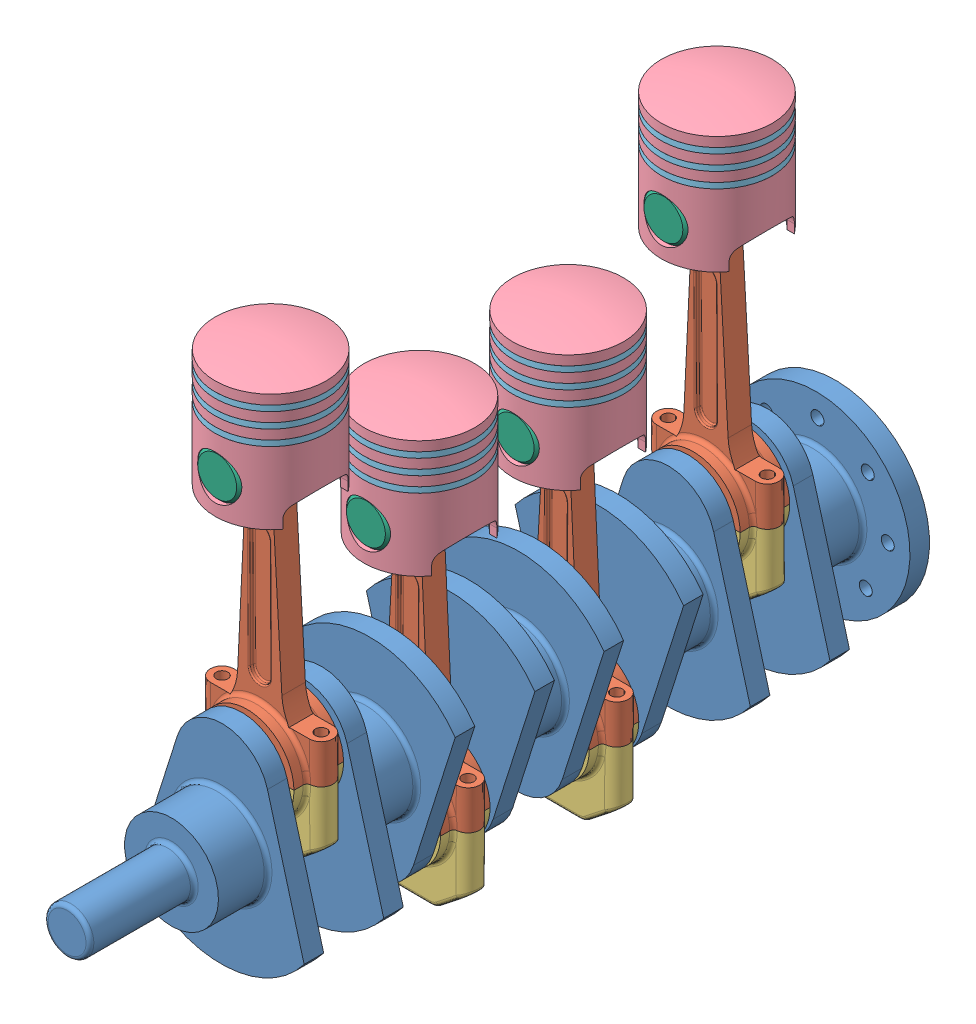
SolidWorks assembly Engine, configuration Default. Lengths in mm.
Overall size (147.06 418.41 589).
29 component instances, 6 part files, 66 mates.
Components (placement in the parent):
- Crankshaft-1: Crankshaft [Default] at (0 0 456) x (-0.999814 0.019293 0) z (0 0 1) size (144 160 589)
- Connecting rod-1: Connecting rod [Default] at (0 245.19 433) x (0.999991 0.004219 0) z (0 0 1) size (94 223.7 38)
- Connecting rod cap-1: Connecting rod cap [Default] at (0.8489 43.9918 433) x (-0.999991 -0.004219 0) z (0 0 1) size (94 60 38)
- Piston-1: Piston [Default] at (0 219.2199 433) size (85 95 85)
- Piston ring-1: Piston ring [Default] at (0 297.6199 433) size (85 4.3 85)
- Piston Pin-1: Piston Pin [Default] at (0 245.19 433) size (33.8 33.8 82)
- Piston ring-2: Piston ring [Default] at (0 286.0199 433) x (0.546944 0 -0.837169) z (0.837169 0 0.546944) size (85 4.3 85)
- Piston ring-4: Piston ring [Default] at (0 274.4199 433) x (0.546944 0 -0.837169) z (0.837169 0 0.546944) size (85 4.3 85)
- Piston-2: Piston [Default] at (0 131.2362 319) size (85 95 85)
- Piston ring-6: Piston ring [Default] at (0 209.6362 319) x (0.941458 0 -0.337131) z (0.337131 0 0.941458) size (85 4.3 85)
- Piston ring-7: Piston ring [Default] at (0 198.0362 319) x (0.23269 0 -0.972551) z (0.972551 0 0.23269) size (85 4.3 85)
- Piston ring-8: Piston ring [Default] at (0 186.4362 319) x (0.23269 0 -0.972551) z (0.972551 0 0.23269) size (85 4.3 85)
- Piston Pin-2: Piston Pin [Default] at (0 157.2064 319) x (0.216826 -0.97621 0) z (0 0 1) size (33.8 33.8 82)
- Connecting rod-2: Connecting rod [Default] at (0 157.2064 319) x (0.999991 -0.004219 0) z (0 0 1) size (94 223.7 38)
- Connecting rod cap-2: Connecting rod cap [Default] at (-0.8489 -43.9918 319) x (-0.999991 0.004219 0) z (0 0 1) size (94 60 38)
- Piston-4: Piston [Default] at (0 131.2362 205) x (-1 0 0) z (0 0 -1) size (85 95 85)
- Piston ring-12: Piston ring [Default] at (0 209.6362 205) x (0.790546 0 -0.612403) z (0.612403 0 0.790546) size (85 4.3 85)
- Piston ring-13: Piston ring [Default] at (0 198.0362 205) x (-0.0803 0 -0.996771) z (0.996771 0 -0.0803) size (85 4.3 85)
- Piston ring-14: Piston ring [Default] at (0 186.4362 205) x (-0.0803 0 -0.996771) z (0.996771 0 -0.0803) size (85 4.3 85)
- Piston Pin-4: Piston Pin [Default] at (0 157.2064 205) x (-0.34202 0.939693 0) z (0 0 -1) size (33.8 33.8 82)
- Connecting rod-4: Connecting rod [Default] at (0 157.2064 205) x (-0.999991 0.004219 0) z (0 0 -1) size (94 223.7 38)
- Connecting rod cap-4: Connecting rod cap [Default] at (-0.8489 -43.9918 205) x (0.999991 -0.004219 0) z (0 0 -1) size (94 60 38)
- Piston-6: Piston [Default] at (0 219.2199 91) x (-1 0 0) z (0 0 -1) size (85 95 85)
- Piston ring-18: Piston ring [Default] at (0 297.6199 91) x (0.6 0 -0.8) z (0.8 0 0.6) size (85 4.3 85)
- Piston ring-19: Piston ring [Default] at (0 286.0199 91) x (-0.341569 0 -0.939857) z (0.939857 0 -0.341569) size (85 4.3 85)
- Piston ring-20: Piston ring [Default] at (0 274.4199 91) x (-0.341569 0 -0.939857) z (0.939857 0 -0.341569) size (85 4.3 85)
- Piston Pin-6: Piston Pin [Default] at (0 245.19 91) x (-0.5 0.866025 0) z (0 0 -1) size (33.8 33.8 82)
- Connecting rod-6: Connecting rod [Default] at (0 245.19 91) x (-0.999991 -0.004219 0) z (0 0 -1) size (94 223.7 38)
- Connecting rod cap-6: Connecting rod cap [Default] at (0.8489 43.9918 91) x (0.999991 0.004219 0) z (0 0 -1) size (94 60 38)
Mates (geometry in assembly coordinates):
- Concentric1: concentric anti-aligned: cylinder of Crankshaft-1 through (0 0 589) axis (0 0 -1) radius 17.5
- Coincident1: coincident: plane of Crankshaft-1 through (0 0 589) normal (0 0 1)
- Coincident2: coincident aligned: plane of Piston-1 through (0 219.2199 433) normal (0 0 1); plane of Piston Pin-1 through (0 245.19 433) normal (0 0 1)
- Concentric2: concentric anti-aligned: cylinder of Piston-1 through (0 245.19 390.5) axis (0 0 1) radius 16.9; cylinder of Piston Pin-1 through (0 245.19 474) axis (0 0 -1) radius 16.9
- Concentric3: concentric aligned: cylinder of Piston-1 through (0 309.2199 433) axis (0 -1 0) radius 42.5; cylinder of Piston ring-1 through (0 301.9199 433) axis (0 -1 0) radius 42.5
- Coincident3: coincident anti-aligned: plane of Piston-1 through (0 297.6199 433) normal (0 1 0); plane of Piston ring-1 through (0 297.6199 433) normal (0 -1 0)
- Concentric4: concentric anti-aligned: cylinder of Piston-1 through (0 286.0199 433) axis (0 1 0) radius 39.5; cylinder of Piston ring-2 through (0 290.3199 433) axis (0 -1 0) radius 42.5
- Coincident4: coincident anti-aligned: plane of Piston-1 through (0 286.0199 433) normal (0 1 0); plane of Piston ring-2 through (0 286.0199 433) normal (0 -1 0)
- Concentric5: concentric anti-aligned: cylinder of Piston-1 through (0 274.4199 433) axis (0 1 0) radius 39.5; cylinder of Piston ring-4 through (0 278.7199 433) axis (0 -1 0) radius 42.5
- Coincident5: coincident anti-aligned: plane of Piston-1 through (0 274.4199 433) normal (0 1 0); plane of Piston ring-4 through (0 274.4199 433) normal (0 -1 0)
- Coincident6: coincident aligned: plane of Connecting rod-1 through (0 245.19 433) normal (0 0 1); plane of Piston-1 through (0 219.2199 433) normal (0 0 1)
- Concentric6: concentric aligned: cylinder of Connecting rod-1 through (0 245.19 452) axis (0 0 -1) radius 16.9; cylinder of Piston Pin-1 through (0 245.19 474) axis (0 0 -1) radius 16.9
- Concentric7: concentric aligned: cylinder of Connecting rod-1 through (38.8486 44.1521 433) axis (-0.004219 0.999991 0) radius 4.5; cylinder of Connecting rod cap-1 through (39.1017 -15.8473 433) axis (-0.004219 0.999991 0) radius 4.5
- Concentric8: concentric aligned: cylinder of Connecting rod-1 through (-37.1508 43.8315 433) axis (-0.004219 0.999991 0) radius 4.5; cylinder of Connecting rod cap-1 through (-36.8976 -16.168 433) axis (-0.004219 0.999991 0) radius 4.5
- Coincident7: coincident anti-aligned: plane of Connecting rod-1 through (0.8489 43.9918 452) normal (0.004219 -0.999991 0); plane of Connecting rod cap-1 through (36.8486 44.1437 452) normal (-0.004219 0.999991 0)
- Width1: width anti-aligned: plane of Crankshaft-1 through (0 0 410) normal (0 0 1); plane of Connecting rod-1 through (0 0 456) normal (0 0 -1); plane of Crankshaft-1 through (0 245.19 424) normal (0 0 -1); plane of Connecting rod-1 through (0 245.19 442) normal (0 0 1)
- Concentric9: concentric anti-aligned: cylinder of Crankshaft-1 through (0.8489 43.9918 410) axis (0 0 1) radius 27; cylinder of Connecting rod-1 through (0.8489 43.9918 452) axis (0 0 -1) radius 27
- Concentric10: concentric anti-aligned: cylinder of Piston-1 through (0 309.2199 433) axis (0 -1 0) radius 42.5
- Coincident9: coincident aligned: plane of Piston-2 through (0 131.2362 319) normal (0 0 1); plane of Piston Pin-2 through (0 157.2064 319) normal (0 0 1)
- Concentric11: concentric anti-aligned: cylinder of Piston-2 through (0 157.2064 276.5) axis (0 0 1) radius 16.9; cylinder of Piston Pin-2 through (0 157.2064 360) axis (0 0 -1) radius 16.9
- Concentric12: concentric aligned: cylinder of Piston-2 through (0 221.2362 319) axis (0 -1 0) radius 42.5; cylinder of Piston ring-6 through (0 213.9362 319) axis (0 -1 0) radius 42.5
- Coincident10: coincident anti-aligned: plane of Piston-2 through (0 209.6362 319) normal (0 1 0); plane of Piston ring-6 through (0 209.6362 319) normal (0 -1 0)
- Concentric13: concentric anti-aligned: cylinder of Piston-2 through (0 198.0362 319) axis (0 1 0) radius 39.5; cylinder of Piston ring-7 through (0 202.3362 319) axis (0 -1 0) radius 42.5
- Coincident11: coincident anti-aligned: plane of Piston-2 through (0 198.0362 319) normal (0 1 0); plane of Piston ring-7 through (0 198.0362 319) normal (0 -1 0)
- Concentric14: concentric anti-aligned: cylinder of Piston-2 through (0 186.4362 319) axis (0 1 0) radius 39.5; cylinder of Piston ring-8 through (0 190.7362 319) axis (0 -1 0) radius 42.5
- Coincident12: coincident anti-aligned: plane of Piston-2 through (0 186.4362 319) normal (0 1 0); plane of Piston ring-8 through (0 186.4362 319) normal (0 -1 0)
- Coincident13: coincident aligned: plane of Piston-2 through (0 131.2362 319) normal (0 0 1); plane of Connecting rod-2 through (0 157.2064 319) normal (0 0 1)
- Concentric15: concentric aligned: cylinder of Piston Pin-2 through (0 157.2064 360) axis (0 0 -1) radius 16.9; cylinder of Connecting rod-2 through (0 157.2064 338) axis (0 0 -1) radius 16.9
- Concentric16: concentric aligned: cylinder of Connecting rod-2 through (37.1508 -44.1521 319) axis (0.004219 0.999991 0) radius 4.5; cylinder of Connecting rod cap-2 through (36.8976 -104.1516 319) axis (0.004219 0.999991 0) radius 4.5
- Concentric17: concentric aligned: cylinder of Connecting rod-2 through (-38.8486 -43.8315 319) axis (0.004219 0.999991 0) radius 4.5; cylinder of Connecting rod cap-2 through (-39.1017 -103.8309 319) axis (0.004219 0.999991 0) radius 4.5
- Coincident14: coincident anti-aligned: plane of Connecting rod-2 through (-0.8489 -43.9918 338) normal (-0.004219 -0.999991 0); plane of Connecting rod cap-2 through (35.1508 -44.1437 338) normal (0.004219 0.999991 0)
- Width2: width anti-aligned: plane of Crankshaft-1 through (0 0 342) normal (0 0 -1); plane of Connecting rod-2 through (0 0 296) normal (0 0 1); plane of Crankshaft-1 through (0 157.2064 310) normal (0 0 -1); plane of Connecting rod-2 through (0 157.2064 328) normal (0 0 1)
- Concentric18: concentric anti-aligned: cylinder of Crankshaft-1 through (-0.8489 -43.9918 296) axis (0 0 1) radius 27; cylinder of Connecting rod-2 through (-0.8489 -43.9918 338) axis (0 0 -1) radius 27
- Concentric19: concentric anti-aligned: cylinder of Piston-2 through (0 221.2362 319) axis (0 -1 0) radius 42.5
- Coincident21: coincident aligned: plane of Piston-4 through (0 131.2362 205) normal (0 0 -1); plane of Piston Pin-4 through (0 157.2064 205) normal (0 0 -1)
- Concentric27: concentric anti-aligned: cylinder of Piston-4 through (0 157.2064 247.5) axis (0 0 -1) radius 16.9; cylinder of Piston Pin-4 through (0 157.2064 164) axis (0 0 1) radius 16.9
- Concentric28: concentric aligned: cylinder of Piston-4 through (0 221.2362 205) axis (0 -1 0) radius 42.5; cylinder of Piston ring-12 through (0 213.9362 205) axis (0 -1 0) radius 42.5
- Coincident22: coincident anti-aligned: plane of Piston-4 through (0 209.6362 205) normal (0 1 0); plane of Piston ring-12 through (0 209.6362 205) normal (0 -1 0)
- Concentric29: concentric anti-aligned: cylinder of Piston-4 through (0 198.0362 205) axis (0 1 0) radius 39.5; cylinder of Piston ring-13 through (0 202.3362 205) axis (0 -1 0) radius 42.5
- Coincident23: coincident anti-aligned: plane of Piston-4 through (0 198.0362 205) normal (0 1 0); plane of Piston ring-13 through (0 198.0362 205) normal (0 -1 0)
- Concentric30: concentric anti-aligned: cylinder of Piston-4 through (0 186.4362 205) axis (0 1 0) radius 39.5; cylinder of Piston ring-14 through (0 190.7362 205) axis (0 -1 0) radius 42.5
- Coincident24: coincident anti-aligned: plane of Piston-4 through (0 186.4362 205) normal (0 1 0); plane of Piston ring-14 through (0 186.4362 205) normal (0 -1 0)
- Coincident25: coincident aligned: plane of Piston-4 through (0 131.2362 205) normal (0 0 -1); plane of Connecting rod-4 through (0 157.2064 205) normal (0 0 -1)
- Concentric31: concentric aligned: cylinder of Piston Pin-4 through (0 157.2064 164) axis (0 0 1) radius 16.9; cylinder of Connecting rod-4 through (0 157.2064 186) axis (0 0 1) radius 16.9
- Concentric32: concentric aligned: cylinder of Connecting rod-4 through (-38.8486 -43.8315 205) axis (0.004219 0.999991 0) radius 4.5; cylinder of Connecting rod cap-4 through (-39.1017 -103.8309 205) axis (0.004219 0.999991 0) radius 4.5
- Concentric33: concentric aligned: cylinder of Connecting rod-4 through (37.1508 -44.1521 205) axis (0.004219 0.999991 0) radius 4.5; cylinder of Connecting rod cap-4 through (36.8976 -104.1516 205) axis (0.004219 0.999991 0) radius 4.5
- Coincident26: coincident anti-aligned: plane of Connecting rod-4 through (-0.8489 -43.9918 186) normal (-0.004219 -0.999991 0); plane of Connecting rod cap-4 through (-36.8486 -43.8399 186) normal (0.004219 0.999991 0)
- Width3: width anti-aligned: plane of Crankshaft-1 through (0 0 228) normal (0 0 -1); plane of Connecting rod-4 through (0 0 182) normal (0 0 1); plane of Crankshaft-1 through (0 157.2064 214) normal (0 0 1); plane of Connecting rod-4 through (0 157.2064 196) normal (0 0 -1)
- Concentric34: concentric anti-aligned: cylinder of Crankshaft-1 through (-0.8489 -43.9918 228) axis (0 0 -1) radius 27; cylinder of Connecting rod-4 through (-0.8489 -43.9918 186) axis (0 0 1) radius 27
- Concentric35: concentric anti-aligned: cylinder of Piston-4 through (0 221.2362 205) axis (0 -1 0) radius 42.5
- Coincident33: coincident aligned: plane of Piston-6 through (0 219.2199 91) normal (0 0 -1); plane of Piston Pin-6 through (0 245.19 91) normal (0 0 -1)
- Concentric43: concentric anti-aligned: cylinder of Piston-6 through (0 245.19 133.5) axis (0 0 -1) radius 16.9; cylinder of Piston Pin-6 through (0 245.19 50) axis (0 0 1) radius 16.9
- Concentric44: concentric aligned: cylinder of Piston-6 through (0 309.2199 91) axis (0 -1 0) radius 42.5; cylinder of Piston ring-18 through (0 301.9199 91) axis (0 -1 0) radius 42.5
- Coincident34: coincident anti-aligned: plane of Piston-6 through (0 297.6199 91) normal (0 1 0); plane of Piston ring-18 through (0 297.6199 91) normal (0 -1 0)
- Concentric45: concentric anti-aligned: cylinder of Piston-6 through (0 286.0199 91) axis (0 1 0) radius 39.5; cylinder of Piston ring-19 through (0 290.3199 91) axis (0 -1 0) radius 42.5
- Coincident35: coincident anti-aligned: plane of Piston-6 through (0 286.0199 91) normal (0 1 0); plane of Piston ring-19 through (0 286.0199 91) normal (0 -1 0)
- Concentric46: concentric anti-aligned: cylinder of Piston-6 through (0 274.4199 91) axis (0 1 0) radius 39.5; cylinder of Piston ring-20 through (0 278.7199 91) axis (0 -1 0) radius 42.5
- Coincident36: coincident anti-aligned: plane of Piston-6 through (0 274.4199 91) normal (0 1 0); plane of Piston ring-20 through (0 274.4199 91) normal (0 -1 0)
- Coincident37: coincident aligned: plane of Piston-6 through (0 219.2199 91) normal (0 0 -1); plane of Connecting rod-6 through (0 245.19 91) normal (0 0 -1)
- Concentric47: concentric aligned: cylinder of Piston Pin-6 through (0 245.19 50) axis (0 0 1) radius 16.9; cylinder of Connecting rod-6 through (0 245.19 72) axis (0 0 1) radius 16.9
- Concentric48: concentric aligned: cylinder of Connecting rod-6 through (-37.1508 43.8315 91) axis (-0.004219 0.999991 0) radius 4.5; cylinder of Connecting rod cap-6 through (-36.8976 -16.168 91) axis (-0.004219 0.999991 0) radius 4.5
- Concentric49: concentric aligned: cylinder of Connecting rod-6 through (38.8486 44.1521 91) axis (-0.004219 0.999991 0) radius 4.5; cylinder of Connecting rod cap-6 through (39.1017 -15.8473 91) axis (-0.004219 0.999991 0) radius 4.5
- Coincident38: coincident anti-aligned: plane of Connecting rod-6 through (0.8489 43.9918 72) normal (0.004219 -0.999991 0); plane of Connecting rod cap-6 through (-35.1508 43.8399 72) normal (-0.004219 0.999991 0)
- Width4: width anti-aligned: plane of Crankshaft-1 through (0 0 114) normal (0 0 -1); plane of Connecting rod-6 through (0 0 68) normal (0 0 1); plane of Crankshaft-1 through (0 245.19 100) normal (0 0 1); plane of Connecting rod-6 through (0 245.19 82) normal (0 0 -1)
- Concentric50: concentric anti-aligned: cylinder of Crankshaft-1 through (0.8489 43.9918 114) axis (0 0 -1) radius 27; cylinder of Connecting rod-6 through (0.8489 43.9918 72) axis (0 0 1) radius 27
- Concentric51: concentric anti-aligned: cylinder of Piston-6 through (0 309.2199 91) axis (0 -1 0) radius 42.5
